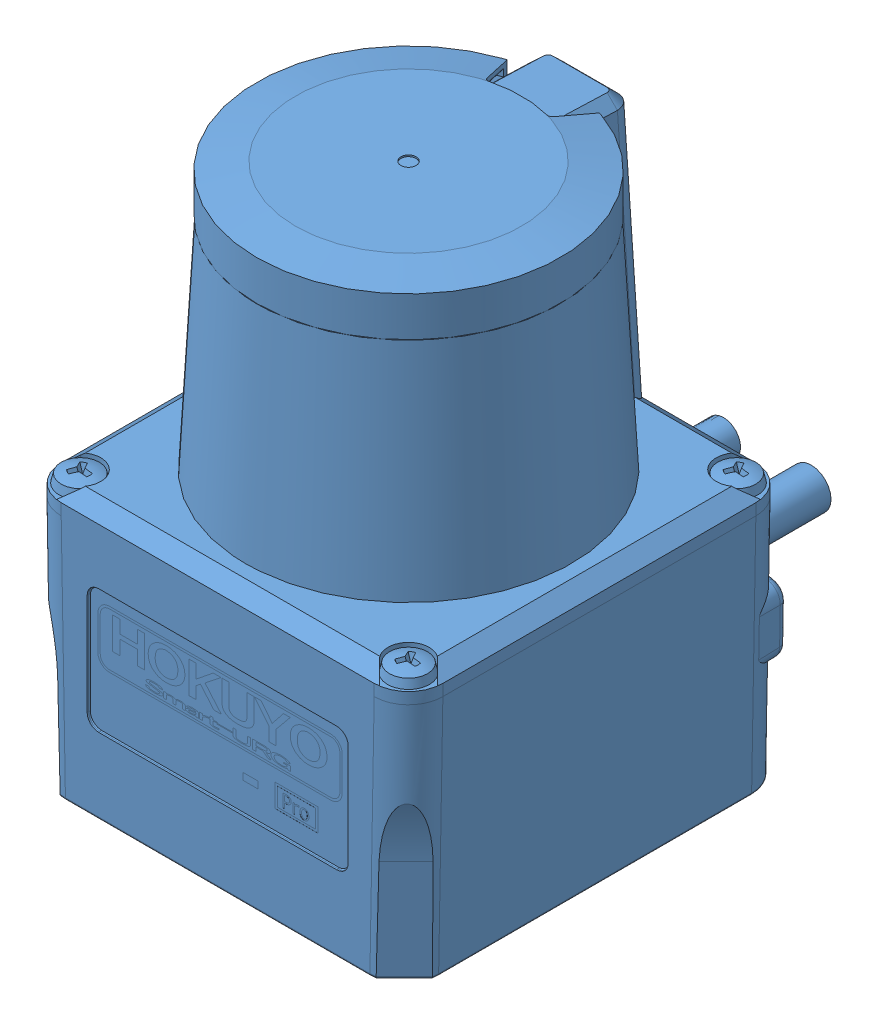
SolidWorks assembly UST-30LX, configuration ﾃﾞﾌｫﾙﾄ. Lengths in mm.
Overall size (50.01 70.01 72.01).
5 component instances, 2 part files, 0 mates.
Components (placement in the parent):
- Copy of SWP-02205^UST-30LX-1: Copy of SWP-02205^UST-30LX [ﾃﾞﾌｫﾙﾄ] at origin size (50.01 70.01 72.01) (virtual)
- Copy of M2ｘ5.5_TM3022_三つ矢_三価黒^UST-30LX-1: Copy of M2ｘ5.5_TM3022_三つ矢_三価黒^UST-30LX [ﾃﾞﾌｫﾙﾄ] at (16.7 32.3 -24.6969) x (-0.213413 -0.976962 0) z (0 0 -1) size (3.5 3.5 6.1) (virtual)
- Copy of M2ｘ5.5_TM3022_三つ矢_三価黒^UST-30LX-2: Copy of M2ｘ5.5_TM3022_三つ矢_三価黒^UST-30LX [ﾃﾞﾌｫﾙﾄ] at (-16.7 32.3 -24.6969) x (-0.213413 -0.976962 0) z (0 0 -1) size (3.5 3.5 6.1) (virtual)
- Copy of M2ｘ5.5_TM3022_三つ矢_三価黒^UST-30LX-3: Copy of M2ｘ5.5_TM3022_三つ矢_三価黒^UST-30LX [ﾃﾞﾌｫﾙﾄ] at (-16.7 13.9 -24.6969) x (-0.213413 -0.976962 0) z (0 0 -1) size (3.5 3.5 6.1) (virtual)
- Copy of M2ｘ5.5_TM3022_三つ矢_三価黒^UST-30LX-4: Copy of M2ｘ5.5_TM3022_三つ矢_三価黒^UST-30LX [ﾃﾞﾌｫﾙﾄ] at (16.7 13.9 -24.6969) x (-0.213413 -0.976962 0) z (0 0 -1) size (3.5 3.5 6.1) (virtual)
